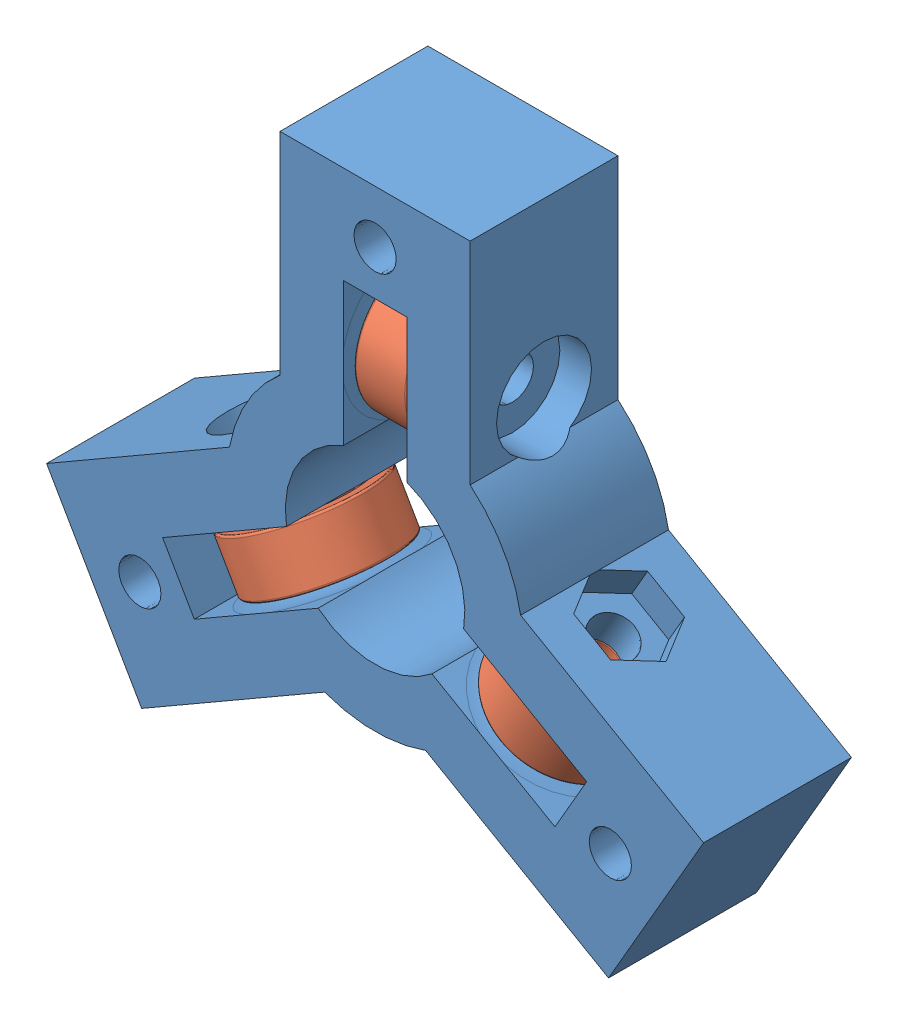
SolidWorks assembly 16mm  printable linear bearing, configuration По умолчанию. Lengths in mm.
Overall size (62.22 53.88 14).
4 component instances, 2 part files, 6 mates.
Components (placement in the parent):
- Bearing frame-1: Bearing frame [По умолчанию] at (-4.3516 -2.6706 55.2152) size (62.22 53.88 14)
- radial ball bearing_68_din-1: radial ball bearing_68_din [DIN 625 - 624 - 8,SI,NC,8_68] at (-16.909 -9.9206 62.2152) x (0.5 -0.866025 0) z (0 0 1) size (5 13 13)
- radial ball bearing_68_din-2: radial ball bearing_68_din [DIN 625 - 624 - 8,SI,NC,8_68] at (8.2057 -9.9206 62.2152) x (0.5 0.866025 0) z (0 0 1) size (5 13 13)
- radial ball bearing_68_din-3: radial ball bearing_68_din [DIN 625 - 624 - 8,SI,NC,8_68] at (-4.3516 11.8294 62.2152) size (5 13 13)
Mates (geometry in assembly coordinates):
- Концентричный1: concentric aligned: cylinder of Bearing frame-1 through (-14.3516 11.8294 62.2152) axis (1 0 0) radius 2; cylinder of radial ball bearing_68_din-3 through (-24.9891 11.8294 62.2152) axis (1 0 0) radius 2
- Концентричный2: concentric anti-aligned: cylinder of Bearing frame-1 through (13.2057 -1.2604 62.2152) axis (-0.5 -0.866025 0) radius 2; cylinder of radial ball bearing_68_din-2 through (-2.113 -27.7932 62.2152) axis (0.5 0.866025 0) radius 2
- Концентричный3: concentric anti-aligned: cylinder of Bearing frame-1 through (-11.909 -18.5809 62.2152) axis (-0.5 0.866025 0) radius 2; cylinder of radial ball bearing_68_din-1 through (-27.2278 7.952 62.2152) axis (0.5 -0.866025 0) radius 2
- Совпадение1: coincident anti-aligned: plane of Bearing frame-1 through (-18.159 -7.7556 62.2152) normal (0.5 -0.866025 0); plane of radial ball bearing_68_din-1 through (-15.2578 -6.0806 62.2152) normal (-0.5 0.866025 0)
- Совпадение2: coincident anti-aligned: plane of Bearing frame-1 through (9.4557 -7.7556 62.2152) normal (-0.5 -0.866025 0); plane of radial ball bearing_68_din-2 through (7.5505 -6.6556 62.2152) normal (0.5 0.866025 0)
- Совпадение3: coincident anti-aligned: plane of Bearing frame-1 through (-6.8516 11.8294 62.2152) normal (1 0 0); plane of radial ball bearing_68_din-3 through (-6.8516 15.1794 62.2152) normal (-1 0 0)
